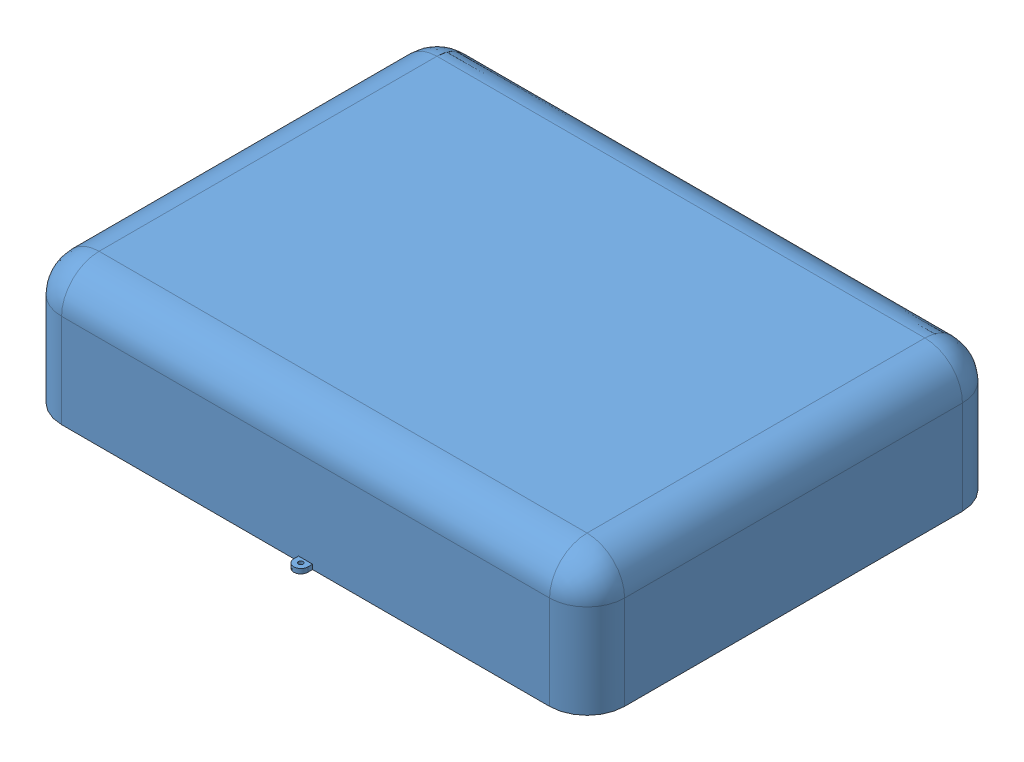
SolidWorks assembly Top Lid Assembly, configuration Default. Lengths in mm.
Overall size (762 187.33 778.42).
3 component instances, 3 part files, 6 mates.
Components (placement in the parent):
- Lid 2.0-1: Lid 2.0 [Default] at (-23.9662 -83.0978 -78.8213) size (762 187.33 778.42)
- Top Insulation-1: Top Insulation [Default] at (-23.9662 89.9397 -78.8213) x (-1 0 0) z (0 0 1) size (752.48 173.04 549.27)
- Top Foam-1: Top Foam [Default] at (-23.9662 83.5897 -78.8213) x (-1 0 0) z (0 0 1) size (739.77 166.69 536.58)
Mates (geometry in assembly coordinates):
- Coincident2: coincident anti-aligned: plane of Top Insulation-1 through (-400.2037 -83.0978 195.8162) normal (0 0 1); plane of Lid 2.0-1 through (357.0338 94.7022 195.8162) normal (0 0 -1)
- Coincident3: coincident anti-aligned: plane of Lid 2.0-1 through (352.2713 94.7022 200.5787) normal (-1 0 0); plane of Top Insulation-1 through (352.2713 -83.0978 195.8162) normal (1 0 0)
- Coincident4: coincident anti-aligned: plane of Lid 2.0-1 through (-23.9662 89.9397 -78.8213) normal (0 -1 0); plane of Top Insulation-1 through (-23.9662 89.9397 -78.8213) normal (0 1 0)
- Coincident5: coincident anti-aligned: plane of Top Insulation-1 through (-23.9662 83.5897 -78.8213) normal (0 -1 0); plane of Top Foam-1 through (-23.9662 83.5897 -78.8213) normal (0 1 0)
- Coincident6: coincident anti-aligned: plane of Top Insulation-1 through (-400.2037 -83.0978 189.4662) normal (0 0 -1); plane of Top Foam-1 through (-393.8537 -83.0978 189.4662) normal (0 0 1)
- Coincident7: coincident anti-aligned: plane of Top Insulation-1 through (345.9213 -83.0978 195.8162) normal (-1 0 0); plane of Top Foam-1 through (345.9213 -83.0978 189.4662) normal (1 0 0)
